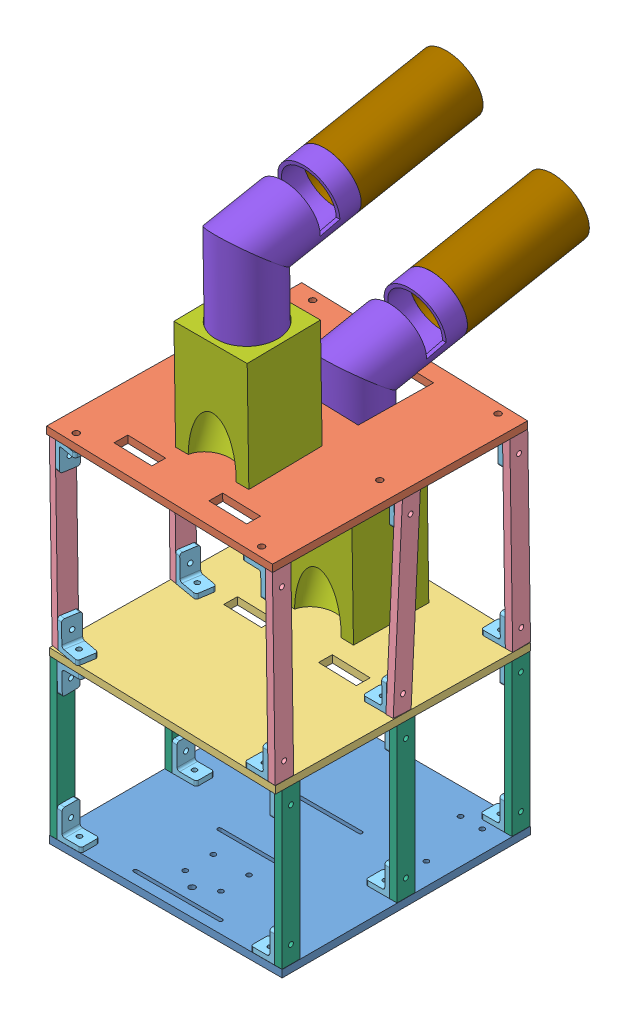
SolidWorks assembly Assem1, configuration Default. Lengths in mm.
Overall size (196.89 498.4 334.99).
47 component instances, 9 part files, 68 mates.
Components (placement in the parent):
- Chassis Base 2-1: Chassis Base 2 [Default] at (104.2216 89.0275 150.5221) size (190.5 6 203.2)
- upper base-1: upper base [Default] at (106.8957 381.7847 155.4014) x (0.999587 -0.000431 0.028738) z (-0.028741 -0.014976 0.999475) size (190.5 6 203.2)
- lower base-1: lower base [Default] at (106.8957 223.4025 153.0283) x (0.999587 -0.000431 0.028738) z (-0.028741 -0.014976 0.999475) size (190.5 6 203.2)
- stand-1: stand [Default] at (14.604 307.0443 57.413) x (0.028741 0.014976 -0.999475) z (0.999587 -0.000431 0.028738) size (14.68 152.4 6)
- stand holder-1: stand holder [Default] at (26.5259 229.4121 152.4299) x (0.985617 -0.002532 0.168977) z (-0.168996 -0.014766 0.985506) size (19.7 24 14.68)
- stand2.1-1: stand2.1 [Default] at (9.1842 158.5275 244.6872) x (0 0 -1) z (1 0 0) size (14.68 127 6)
- stand holder-2: stand holder [Default] at (24.1148 95.0275 152.4329) size (19.7 24 14.68)
- stand holder-3: stand holder [Default] at (29.4735 230.8178 58.6102) x (0.999587 -0.000431 0.028738) z (-0.028741 -0.014976 0.999475) size (19.7 24 14.68)
- stand holder-4: stand holder [Default] at (24.1148 95.0275 246.598) size (19.7 24 14.68)
- stand holder-5: stand holder [Default] at (24.1148 95.0275 58.2678) size (19.7 24 14.68)
- stand holder-6: stand holder [Default] at (23.8029 228.0023 246.5217) x (0.983752 -0.00269 0.179513) z (-0.179533 -0.014738 0.983641) size (19.7 24 14.68)
- stand2.1-2: stand2.1 [Default] at (9.1842 158.5275 150.5221) x (0 0 -1) z (1 0 0) size (14.68 127 6)
- stand2.1-3: stand2.1 [Default] at (9.1842 158.5275 56.357) x (0 0 -1) z (1 0 0) size (14.68 127 6)
- stand2.1-4: stand2.1 [Default] at (193.259 158.5275 56.357) x (0 0 -1) z (1 0 0) size (14.68 127 6)
- stand2.1-5: stand2.1 [Default] at (193.259 158.5275 244.6872) x (0 0 -1) z (1 0 0) size (14.68 127 6)
- stand2.1-6: stand2.1 [Default] at (193.259 158.5275 150.5221) x (0 0 -1) z (1 0 0) size (14.68 127 6)
- stand holder-7: stand holder [Default] at (184.3283 95.0275 54.4463) x (-1 0 0) z (0 0 -1) size (19.7 24 14.68)
- stand holder-8: stand holder [Default] at (184.3283 95.0275 242.7764) x (-1 0 0) z (0 0 -1) size (19.7 24 14.68)
- stand holder-9: stand holder [Default] at (184.3283 95.0275 148.6113) x (-1 0 0) z (0 0 -1) size (19.7 24 14.68)
- stand holder-10: stand holder [Default] at (184.3283 222.0275 152.4329) x (-1 0 0) z (0 0 1) size (19.7 24 14.68)
- stand holder-11: stand holder [Default] at (184.3283 222.0275 58.2678) x (-1 0 0) z (0 0 1) size (19.7 24 14.68)
- stand holder-12: stand holder [Default] at (184.3283 222.0275 246.598) x (-1 0 0) z (0 0 1) size (19.7 24 14.68)
- stand holder-13: stand holder [Default] at (24.1148 222.0275 54.4463) x (1 0 0) z (0 0 -1) size (19.7 24 14.68)
- stand holder-14: stand holder [Default] at (24.1148 222.0275 148.6113) x (1 0 0) z (0 0 -1) size (19.7 24 14.68)
- stand holder-15: stand holder [Default] at (24.1148 222.0546 242.9864) x (1 0 0) z (0 0.014982 -0.999888) size (19.7 24 14.68)
- stand holder-16: stand holder [Default] at (29.5834 383.258 57.0739) x (0.999587 -0.000431 0.028738) z (0.028741 0.014976 -0.999475) size (19.7 24 14.68)
- stand holder-17: stand holder [Default] at (27.1718 381.8514 150.947) x (0.985617 -0.002532 0.168977) z (0.168996 0.014766 -0.985506) size (19.7 24 14.68)
- stand holder-18: stand holder [Default] at (24.489 380.4415 245.0459) x (0.983752 -0.00269 0.179513) z (0.179533 0.014738 -0.983641) size (19.7 24 14.68)
- stand holder-19: stand holder [Default] at (189.6849 383.1327 65.435) x (-0.999991 -0.000065 0.004336) z (0.004336 -0.014982 0.999878) size (19.7 24 14.68)
- stand holder-20: stand holder [Default] at (186.9704 381.8431 151.5021) x (-1 0 -0.000031) z (-0.000031 -0.014982 0.999888) size (19.7 24 14.68)
- stand holder-21: stand holder [Default] at (184.208 380.3114 253.7289) x (-0.999587 0.000431 -0.028738) z (-0.028741 -0.014976 0.999475) size (19.7 24 14.68)
- stand-2: stand [Default] at (195.9009 305.7505 152.4806) x (0.000031 -0.049815 -0.998758) z (1 0 0.000031) size (14.68 152.4 6)
- stand-3: stand [Default] at (9.458 304.262 243.1036) x (0.179533 0.014738 -0.983641) z (0.983752 -0.00269 0.179513) size (14.68 152.4 6)
- stand-4: stand [Default] at (12.133 305.6696 149.1655) x (0.168996 0.014766 -0.985506) z (0.985617 -0.002532 0.168977) size (14.68 152.4 6)
- stand-5: stand [Default] at (198.6071 306.9705 62.3441) x (-0.004336 0.014982 -0.999878) z (0.999991 0.000065 -0.004336) size (14.68 152.4 6)
- stand-6: stand [Default] at (193.1899 304.1447 250.9342) x (0.028741 0.014976 -0.999475) z (0.999587 -0.000431 0.028738) size (14.68 152.4 6)
- stand holder-22: stand holder [Default] at (189.6683 230.8071 59.3306) x (-0.999991 -0.000065 0.004336) z (-0.004336 0.014982 -0.999878) size (19.7 24 14.68)
- stand holder-23: stand holder [Default] at (184.3179 227.9857 247.6261) x (-0.999587 0.000431 -0.028738) z (0.028741 0.014976 -0.999475) size (19.7 24 14.68)
- stand holder-24: stand holder [Default] at (186.9702 229.6579 153.4585) x (-1 0 -0.000031) z (0.000031 0.014982 -0.999888) size (19.7 24 14.68)
- Part1-1: Part1 [Default] at (104.2743 230.2456 96.8027) x (0.999587 -0.000431 0.028738) z (-0.028741 -0.014976 0.999475) size (60 90 61.34)
- Part1-2: Part1 [Default] at (107.1896 387.31 187.1261) x (1 0 0) z (0 -0.014982 0.999888) size (60 90 61.34)
- cone assembly-1: cone assembly [Default] at (48.4593 435.9679 19.7331) x (1 0 0) z (0 -0.014982 0.999888) size (50 134.42 198.33)
  - angle cone3-1: angle cone3 [Default] at (58.7302 16.9755 168.1031) x (-1 0 0) z (0 -1 0) size (50 98.28 116.78)
  - ball holder ver 2-2: ball holder ver 2 [Default] at (58.7302 109.1309 99.1666) x (1 0 0) z (0 0.984808 0.173648) size (50 101.6 50)
- cone assembly-2: cone assembly [Default] at (45.5522 302.2491 -70.2433) x (1 -0.000001 0.000048) z (-0.000048 -0.014982 0.999888) size (50 134.42 198.33)
  - angle cone3-1: angle cone3 [Default] at (58.7302 16.9755 168.1031) x (-1 0 0) z (0 -1 0) size (50 98.28 116.78)
  - ball holder ver 2-2: ball holder ver 2 [Default] at (58.7302 109.1309 99.1666) x (1 0 0) z (0 0.984808 0.173648) size (50 101.6 50)
Mates (geometry in assembly coordinates):
- Concentric1: concentric anti-aligned: circle of Chassis Base 2-1; circle of stand holder-4
- Coincident1: coincident anti-aligned: plane of Chassis Base 2-1 through (104.2216 95.0275 150.5221) normal (0 1 0); plane of stand holder-4 through (24.1148 95.0275 246.598) normal (0 -1 0)
- Coincident4: coincident aligned: circle of stand2-1; circle of stand holder-4
- Parallel1: parallel anti-aligned: line of Chassis Base 2-1 through (8.9716 95.0275 252.1221) axis (1 0 0); line of stand2-1 through (15.1842 95.0275 252.0272) axis (-1 0 0)
- Parallel2: parallel anti-aligned: line of Chassis Base 2-1 through (8.9716 95.0275 48.9221) axis (0 0 1); line of stand2-1 through (9.1842 95.0275 252.0272) axis (0 0 -1)
- Concentric2: concentric aligned: circle of Chassis Base 2-1; circle of stand holder-2
- Coincident7: coincident anti-aligned: plane of Chassis Base 2-1 through (104.2216 95.0275 150.5221) normal (0 1 0); plane of stand holder-2 through (24.1148 95.0275 152.4329) normal (0 -1 0)
- Coincident8: coincident aligned: circle of stand holder-2; circle of stand2-2
- Concentric3: concentric aligned: circle of Chassis Base 2-1; circle of stand holder-5
- Coincident9: coincident anti-aligned: plane of Chassis Base 2-1 through (104.2216 95.0275 150.5221) normal (0 1 0); plane of stand holder-5 through (24.1148 95.0275 58.2678) normal (0 -1 0)
- Coincident10: coincident aligned: circle of stand holder-5; circle of stand2-3
- Concentric4: concentric anti-aligned: circle of Chassis Base 2-1; circle of stand holder-7
- Coincident12: coincident anti-aligned: plane of Chassis Base 2-1 through (104.2216 95.0275 150.5221) normal (0 1 0); plane of stand holder-7 through (184.3283 95.0275 54.4463) normal (0 -1 0)
- Concentric6: concentric aligned: circle of Chassis Base 2-1; circle of stand holder-9
- Concentric7: concentric aligned: circle of Chassis Base 2-1; circle of stand holder-8
- Coincident13: coincident anti-aligned: plane of Chassis Base 2-1 through (104.2216 95.0275 150.5221) normal (0 1 0); plane of stand holder-8 through (184.3283 95.0275 242.7764) normal (0 -1 0)
- Coincident14: coincident anti-aligned: plane of Chassis Base 2-1 through (104.2216 95.0275 150.5221) normal (0 1 0); plane of stand holder-9 through (184.3283 95.0275 148.6113) normal (0 -1 0)
- Coincident15: coincident anti-aligned: plane of Chassis Base 2-1 through (104.2216 95.0275 150.5221) normal (0 1 0); plane of stand holder-7 through (184.3283 95.0275 54.4463) normal (0 -1 0)
- Coincident17: coincident anti-aligned: circle of stand2-4; circle of stand holder-7
- Coincident18: coincident anti-aligned: circle of stand2-6; circle of stand holder-9
- Coincident20: coincident anti-aligned: circle of stand2-5; circle of stand holder-8
- Coincident21: coincident anti-aligned: circle of stand2-1; circle of stand holder-15
- Coincident22: coincident anti-aligned: circle of stand2-2; circle of stand holder-14
- Coincident24: coincident anti-aligned: circle of stand2-3; circle of stand holder-13
- Coincident25: coincident aligned: circle of stand2-5; circle of stand holder-12
- Coincident26: coincident aligned: circle of stand2-6; circle of stand holder-10
- Coincident27: coincident aligned: circle of stand2-4; circle of stand holder-11
- Concentric8: concentric aligned: circle of lower base-1; circle of stand holder-15
- Coincident28: coincident anti-aligned: plane of lower base-1 through (106.8957 223.4025 153.0283) normal (0 -0.999888 -0.014982); plane of stand holder-15
- Concentric9: concentric anti-aligned: circle of lower base-1; circle of stand holder-6
- Coincident29: coincident anti-aligned: plane of lower base-1 through (106.8957 229.4018 153.1182) normal (0 0.999888 0.014982); plane of stand holder-6 through (23.8029 228.0023 246.5217) normal (0 -0.999888 -0.014982)
- Concentric10: concentric aligned: circle of lower base-1; circle of stand holder-1
- Concentric11: concentric aligned: circle of lower base-1; circle of stand holder-3
- Coincident31: coincident anti-aligned: plane of lower base-1 through (106.8957 229.4018 153.1182) normal (0 0.999888 0.014982); plane of stand holder-3 through (29.4735 230.8178 58.6102) normal (0 -0.999888 -0.014982)
- Concentric12: concentric anti-aligned: circle of lower base-1; circle of stand holder-22
- Coincident32: coincident anti-aligned: plane of lower base-1 through (106.8957 229.4018 153.1182) normal (0 0.999888 0.014982); plane of stand holder-22 through (189.6683 230.8071 59.3306) normal (0 -0.999888 -0.014982)
- Concentric13: concentric aligned: circle of lower base-1; circle of stand holder-24
- Concentric14: concentric aligned: circle of lower base-1; circle of stand holder-23
- Coincident33: coincident aligned: circle of stand holder-6; circle of stand-3
- Coincident34: coincident aligned: circle of stand holder-1; circle of stand-4
- Coincident35: coincident aligned: circle of stand-1; circle of stand holder-3
- Coincident36: coincident anti-aligned: circle of stand-6; circle of stand holder-23
- Coincident38: coincident anti-aligned: circle of stand-2; circle of stand holder-24
- Coincident39: coincident anti-aligned: circle of stand-5; circle of stand holder-22
- Coincident40: coincident anti-aligned: circle of stand holder-18; circle of stand-3
- Coincident41: coincident anti-aligned: circle of stand holder-17; circle of stand-4
- Coincident42: coincident anti-aligned: circle of stand-1; circle of stand holder-16
- Coincident43: coincident aligned: circle of stand holder-19; circle of stand-5
- Coincident44: coincident aligned: circle of stand holder-20; circle of stand-2
- Coincident45: coincident aligned: circle of stand holder-21; circle of stand-6
- Concentric15: concentric aligned: circle of upper base-1; circle of stand holder-18
- Coincident46: coincident anti-aligned: plane of upper base-1 through (106.8957 381.7847 155.4014) normal (0 -0.999888 -0.014982); plane of stand holder-18 through (24.489 380.4415 245.0459) normal (0 0.999888 0.014982)
- Coincident47: coincident aligned: circle of upper base-1; plane of stand holder-20 through (186.9704 381.8431 151.5021) normal (0 0.999888 0.014982)
- Concentric16: concentric anti-aligned: circle of upper base-1; circle of stand holder-21
- Coincident52: coincident anti-aligned: plane of upper base-1 through (106.8957 381.7847 155.4014) normal (0 -0.999888 -0.014982); plane of stand holder-19 through (189.6849 383.1327 65.435) normal (0 0.999888 0.014982)
- Concentric18: concentric anti-aligned: circle of upper base-1; circle of stand holder-16
- Coincident53: coincident aligned: line of stand holder-19 through (198.5753 361.2743 55.817) axis (0 0.999888 0.014982); line of stand-5 through (198.5753 230.889 53.8634) axis (0 0.999888 0.014982)
- Parallel3: parallel anti-aligned: line of upper base-1 through (199.1862 380.2221 259.6853) axis (0.028741 0.014976 -0.999475); line of stand-6 through (199.3984 380.4435 244.9121) axis (-0.028741 -0.014976 0.999475)
- Coincident55: coincident anti-aligned: plane of upper base-1 through (106.8957 381.7847 155.4014) normal (0 -0.999888 -0.014982); plane of stand holder-21 through (184.208 380.3114 253.7289) normal (0 0.999888 0.014982)
- Concentric19: concentric anti-aligned: circle of upper base-1; circle of stand holder-17
- Coincident56: coincident anti-aligned: plane of upper base-1 through (106.8957 381.7847 155.4014) normal (0 -0.999888 -0.014982); plane of stand holder-17 through (27.1718 381.8514 150.947) normal (0 0.999888 0.014982)
- Parallel4: parallel aligned: line of lower base-1 through (205.0265 230.8823 54.3088) axis (-0.999587 0.000431 -0.028738); line of stand holder-3 through (38.5059 230.9526 49.6163) axis (-0.999587 0.000431 -0.028738)
- Parallel5: parallel aligned: line of upper base-1 through (77.7222 388.2211 126.318) axis (0.999587 -0.000431 0.028738); line of Part1-1 through (73.3002 319.8143 126.2639) axis (0.999587 -0.000431 0.028738)
- Coincident58: coincident anti-aligned: plane of lower base-1 through (106.8957 229.4018 153.1182) normal (0 0.999888 0.014982); plane of Part1-1 through (104.15 230.2607 95.7935) normal (0 -0.999888 -0.014982)
- Parallel6: parallel aligned: line of upper base-1 through (79.4467 389.1197 66.3495) axis (-0.028741 -0.014976 0.999475); line of Part1-1 through (75.0247 320.7128 66.2955) axis (-0.028741 -0.014976 0.999475)
- Coincident60: coincident anti-aligned: plane of upper base-1 through (106.8957 387.784 155.4913) normal (0 0.999888 0.014982); plane of Part1-2 through (107.1896 387.31 187.1261) normal (0 -0.999888 -0.014982)
- Concentric22: concentric anti-aligned: circle of Part1-2; circle of cone assembly-1/angle cone3-1
- Concentric23: concentric anti-aligned: circle of Part1-1; circle of cone assembly-2/angle cone3-1
